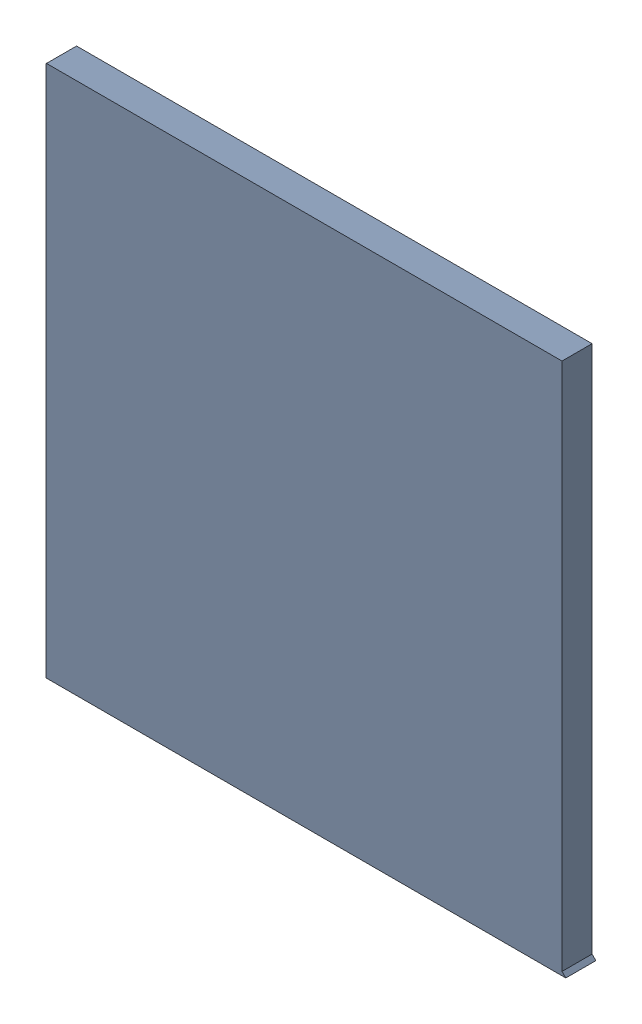
SolidWorks assembly Free-Models, configuration Défaut. Lengths in mm.
Overall size (20.72 21.22 1.2).
2 component instances, 1 part files, 0 mates.
Components (placement in the parent):
- 13909094304-1: 13909094304 [Défaut] at (51.6338 57.7291 0) size (20.72 21.22 1.2)
  - Extruded_1180-1: Extruded_1180 [Défaut] at origin size (20.72 21.22 1.2)
